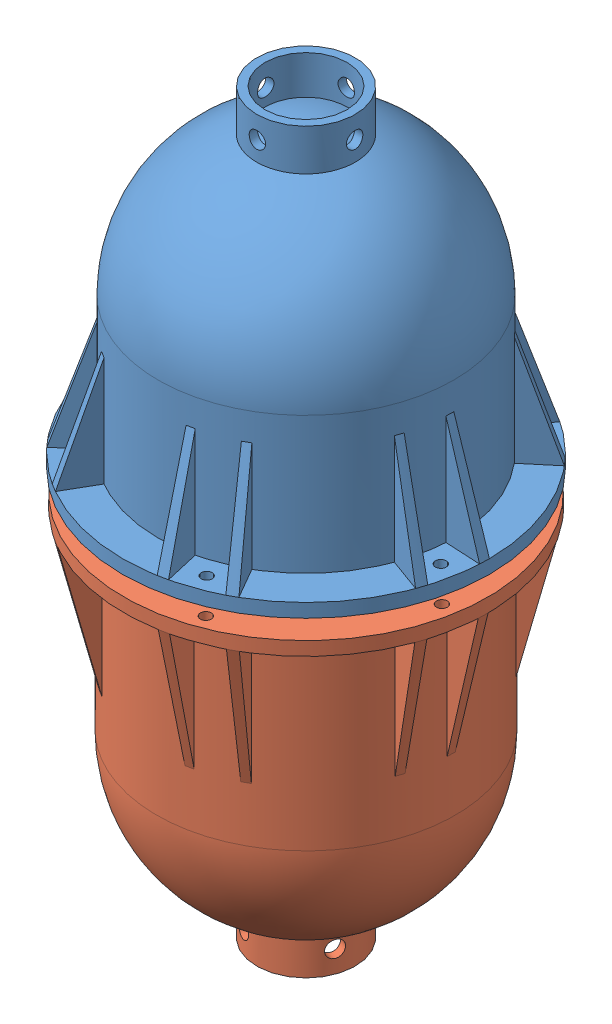
SolidWorks assembly SubsurfaceSensorBuoy Housing, configuration Default. Lengths in mm.
Overall size (170.47 269.41 170.47).
2 component instances, 2 part files, 2 mates.
Components (placement in the parent):
- 4in Flange Housing - Top-1: 4in Flange Housing - Top [Default] at (41.0069 142.6446 106.8525) size (134 130 134)
- 4in Flange Housing - Bottom-1: 4in Flange Housing - Bottom [Default] at (41.0069 5.23 106.8525) x (0.939693 0 0.34202) z (0.34202 0 -0.939693) size (133 141 133)
Mates (geometry in assembly coordinates):
- Coincident9: coincident aligned: plane of 4in Flange Housing - Top-1 through (41.0069 142.6446 106.8525) normal (-0.34202 0 0.939693); plane of 4in Flange Housing - Bottom-1 through (41.0069 5.23 106.8525) normal (-0.34202 0 0.939693)
- Coincident10: coincident aligned: plane of 4in Flange Housing - Top-1 through (41.0069 142.6446 106.8525) normal (0.866025 0 -0.5); plane of 4in Flange Housing - Bottom-1 through (41.0069 5.23 106.8525) normal (0.866025 0 -0.5)
